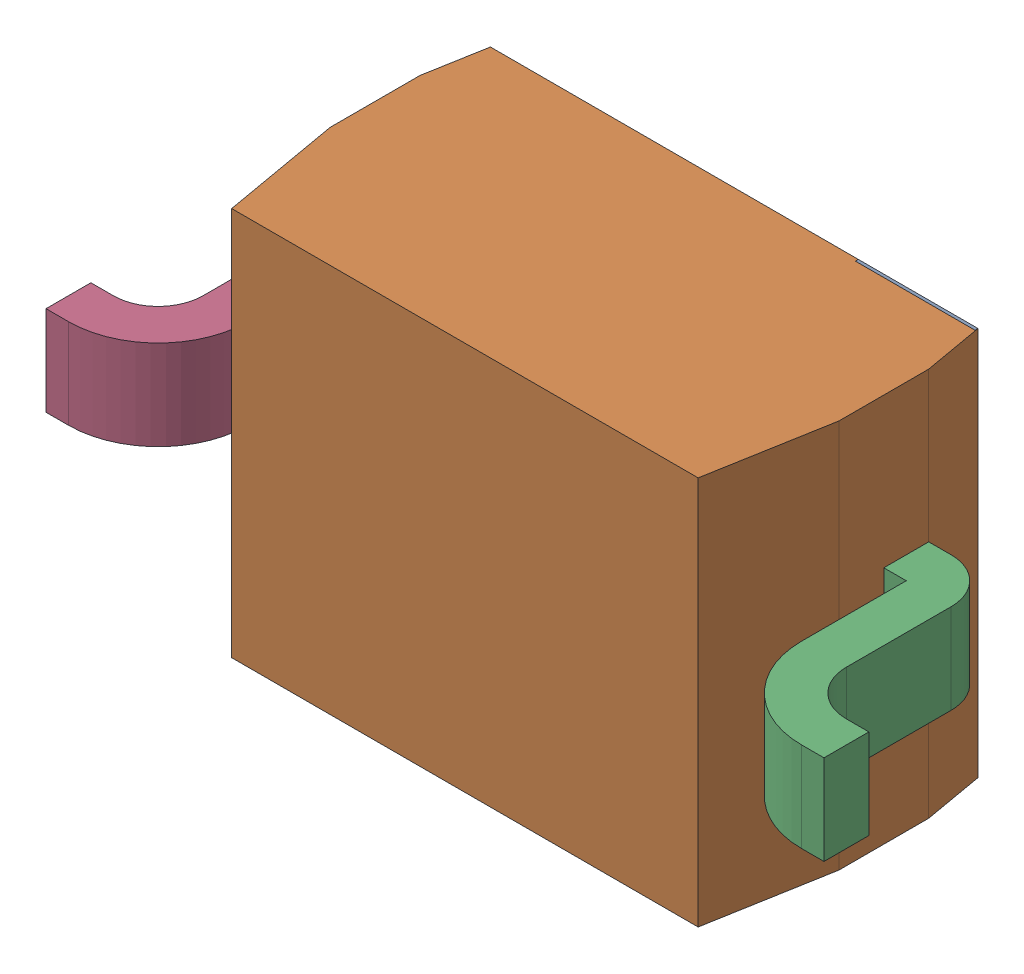
SolidWorks assembly D1, configuration 默认. Lengths in mm.
Overall size (2.6 1.3 1).
5 component instances, 4 part files, 0 mates.
Components (placement in the parent):
- D1-subassembly-1-1: D1-subassembly-1 [默认] at (13.7161 21.5899 -1.6914) x (1 0 0) z (0 0 -1) size (2.6 1.3 1)
  - SOD-323-1: SOD-323 [默认] at origin size (0.4 1.3 0.01)
  - SOD-323-1-1: SOD-323-1 [默认] at origin size (1.7 1.3 0.9)
  - SOD-323-2-1: SOD-323-2 [默认] at origin size (0.45 0.3 0.8)
  - SOD-323-3-1: SOD-323-3 [默认] at origin size (0.45 0.3 0.8)
